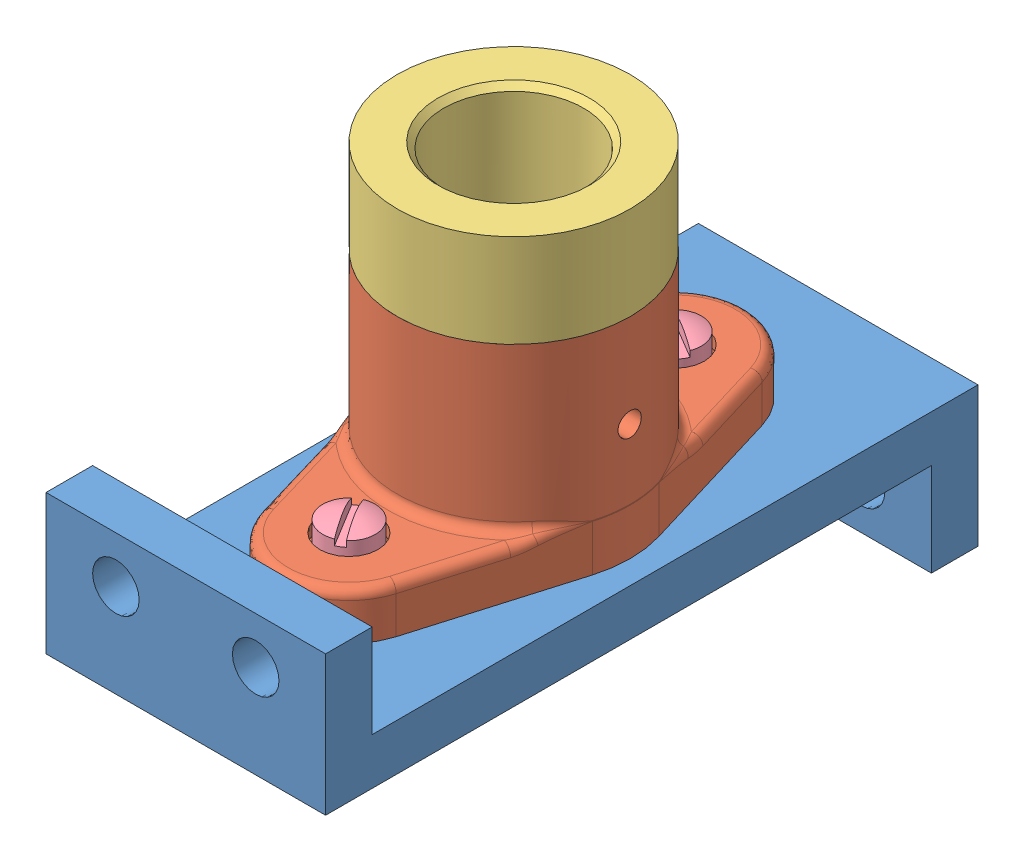
SolidWorks assembly Assembly, configuration Default. Lengths in mm.
Overall size (88.41 120.65 177.8).
5 component instances, 4 part files, 9 mates.
Components (placement in the parent):
- Base_Plate-1: Base_Plate [Default] at (10.3348 113.1985 152.1765) size (76.2 63.5 177.8)
- Bearing-1: Bearing [Default] at (48.4348 100.564 141.6246) size (63.5 57.15 127)
- Collar-1: Collar [Default] at (48.4348 183.114 141.6246) x (0.82007 0 -0.572263) z (0 -1 0) size (63.5 63.5 31.75)
- Cap_Screw-1: Cap_Screw [Default] at (48.4348 115.8716 97.6451) x (0 -1 0) z (0.86001 0 0.510278) size (27.07 14.29 14.29)
- Cap_Screw-2: Cap_Screw [Default] at (48.4484 115.8716 186.5148) x (0 -1 0) z (0.520437 0 0.8539) size (27.07 14.29 14.29)
Mates (geometry in assembly coordinates):
- Concentric1: concentric anti-aligned: cylinder of Base_Plate-1 through (48.4348 24.364 97.6451) axis (0 1 0) radius 4.7625; cylinder of Bearing-1 through (48.4348 113.264 97.6451) axis (0 -1 0) radius 4.7625
- Coincident1: coincident anti-aligned: plane of Base_Plate-1 through (86.5348 100.564 218.2951) normal (0 1 0); plane of Bearing-1 through (48.4348 100.564 141.6246) normal (0 -1 0)
- Concentric2: concentric anti-aligned: cylinder of Base_Plate-1 through (48.4348 24.364 186.5451) axis (0 1 0) radius 4.7625; cylinder of Bearing-1 through (48.4348 113.264 186.5451) axis (0 -1 0) radius 4.7625
- Concentric3: concentric anti-aligned: cylinder of Bearing-1 through (48.4348 113.264 141.6246) axis (0 -1 0) radius 19.05; cylinder of Collar-1 through (48.4348 151.364 141.6246) axis (0 1 0) radius 19.05
- Coincident2: coincident anti-aligned: plane of Bearing-1 through (48.4348 157.714 141.6246) normal (0 1 0); circle of Collar-1
- Tangent2: tangent: cylinder of Bearing-1 through (48.4348 113.264 186.5451) axis (0 -1 0) radius 4.7625; curve of Cap_Screw-2
- Coincident4: coincident anti-aligned: plane of Bearing-1 through (48.4348 110.089 186.5451) normal (0 1 0); plane of Cap_Screw-2 through (54.5484 110.089 182.7969) normal (0 -1 0)
- Concentric4: concentric: sphere of Bearing-1; unknown of Cap_Screw-1
- Coincident6: coincident anti-aligned: plane of Bearing-1 through (48.4348 110.089 97.6451) normal (0 1 0); plane of Cap_Screw-1 through (52.0801 110.089 91.5014) normal (0 -1 0)
